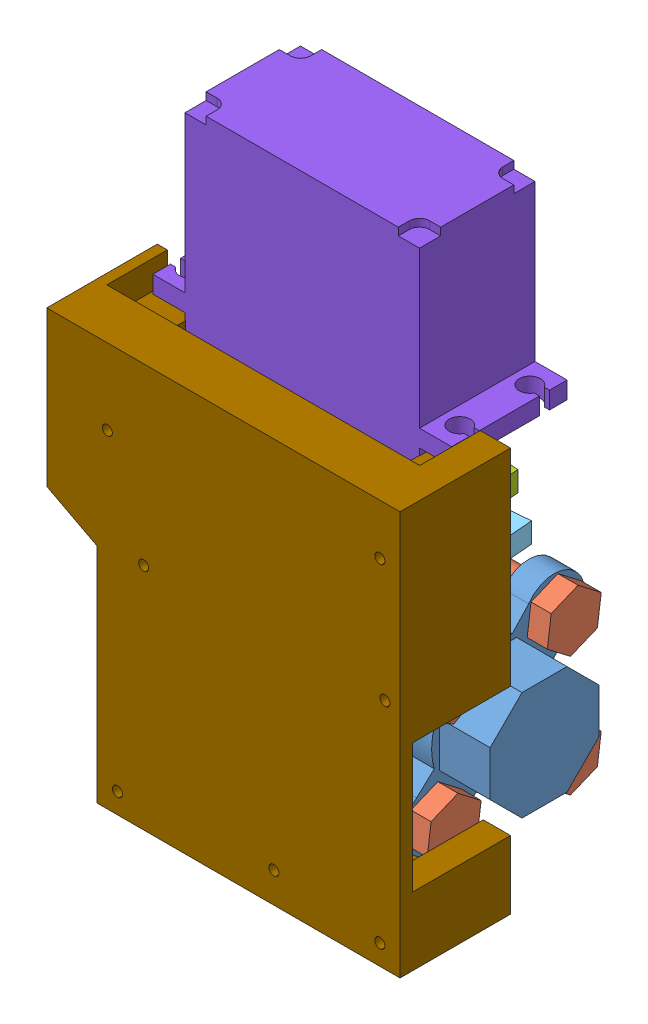
SolidWorks assembly Sharpe 39036 asm, configuration Default. Lengths in mm.
Overall size (89.2 141.62 60.37).
18 component instances, 9 part files, 35 mates.
Components (placement in the parent):
- Sharpe 39036-1: Sharpe 39036 [Default] at (-14.0964 -12.8458 82.9356) size (63.5 64.02 45.72)
- Sharpe 39036 Bolt-1: Sharpe 39036 Bolt [Default] at (29.0836 2.2672 98.0486) x (-1 0 0) z (0 -0.872825 -0.488034) size (53.34 14.66 12.7)
- Sharpe 39036 nut-1: Sharpe 39036 nut [Default] at (-22.6054 2.2672 98.0486) size (6.35 14.66 12.7)
- Sharpe 39036 washer-2: Sharpe 39036 washer [Default] at (-16.2554 2.2672 98.0486) size (2.16 13.21 13.21)
- Sharpe 39036 washer-3: Sharpe 39036 washer [Default] at (-16.2554 2.2672 67.8226) size (2.16 13.21 13.21)
- Sharpe 39036 nut-2: Sharpe 39036 nut [Default] at (-22.6054 -27.9588 98.0486) size (6.35 14.66 12.7)
- Sharpe 39036 Bolt-2: Sharpe 39036 Bolt [Default] at (29.0836 -27.9588 98.0486) x (-1 0 0) z (0 -0.924225 -0.381849) size (53.34 14.66 12.7)
- Sharpe 39036 Bolt-3: Sharpe 39036 Bolt [Default] at (29.0836 2.2672 67.8226) x (-1 0 0) z (0 -0.924225 -0.381849) size (53.34 14.66 12.7)
- Sharpe 39036 Bolt-4: Sharpe 39036 Bolt [Default] at (29.0836 -27.9588 67.8226) x (-1 0 0) z (0 -0.924225 -0.381849) size (53.34 14.66 12.7)
- Sharpe 39036 nut-3: Sharpe 39036 nut [Default] at (-22.6054 2.2672 67.8226) size (6.35 14.66 12.7)
- Sharpe 39036 nut-4: Sharpe 39036 nut [Default] at (-22.6054 -27.9588 67.8226) size (6.35 14.66 12.7)
- Sharpe 39036 washer-4: Sharpe 39036 washer [Default] at (-16.2554 -27.9588 67.8226) size (2.16 13.21 13.21)
- Sharpe 39036 washer-5: Sharpe 39036 washer [Default] at (-16.2554 -27.9588 98.0486) size (2.16 13.21 13.21)
- Horn adapter-1: Horn adapter [Default] at (4.9536 18.539 82.6516) x (-0.996749 0 0.08057) z (-0.08057 0 -0.996749) size (38.1 5.08 16.76)
- 90473A210_LOW-STRENGTH STEEL HEX NUT-1: 90473A210_LOW-STRENGTH STEEL HEX NUT [90473A210] at (4.7267 26.9925 82.6761) x (1 0 0) z (0 1 0) size (12.7 14.66 8.49)
- Servo Horn Mod-1: Servo Horn Mod [Default] at (4.9536 36.5381 82.6516) x (-0.996749 0 0.08057) z (0.08057 0 0.996749) size (37.59 7.67 15.49)
- PowerHD 1235MG-1: PowerHD 1235MG [Default] at (27.5723 54.1403 97.1931) x (-1 0 0) z (0 0 1) size (75.18 62.31 29.08)
- Housing-Front 1.0-1: Housing-Front 1.0 [Default] at (36.402 -46.332 115.818) size (88.9 101.6 27.81)
Mates (geometry in assembly coordinates):
- Coincident5: coincident anti-aligned: plane of Sharpe 39036-1 through (24.0036 -12.8458 82.9356) normal (1 0 0); plane of Sharpe 39036 Bolt-1 through (24.0036 2.2672 98.0486) normal (-1 0 0)
- Concentric4: concentric anti-aligned: cylinder of Sharpe 39036-1 through (24.0036 2.2672 98.0486) axis (-1 0 0) radius 4.7307; cylinder of Sharpe 39036 Bolt-1 through (-24.2564 2.2672 98.0486) axis (1 0 0) radius 3.9688
- Coincident6: coincident anti-aligned: plane of Sharpe 39036-1 through (-14.0964 -12.8458 82.9356) normal (-1 0 0); plane of Sharpe 39036 washer-2 through (-14.0964 2.2672 98.0486) normal (1 0 0)
- Coincident7: coincident aligned: cylinder of Sharpe 39036 Bolt-1 through (-24.2564 2.2672 98.0486) axis (1 0 0) radius 3.9688; circle of Sharpe 39036 washer-2
- Coincident8: coincident anti-aligned: plane of Sharpe 39036 nut-1 through (-16.2554 2.2672 98.0486) normal (1 0 0); plane of Sharpe 39036 washer-2 through (-16.2554 2.2672 98.0486) normal (-1 0 0)
- Concentric5: concentric anti-aligned: cylinder of Sharpe 39036 Bolt-1 through (-24.2564 2.2672 98.0486) axis (1 0 0) radius 3.9688; cylinder of Sharpe 39036 nut-1 through (-16.2554 2.2672 98.0486) axis (-1 0 0) radius 3.9688
- Coincident9: coincident anti-aligned: plane of Sharpe 39036-1 through (24.0036 -12.8458 82.9356) normal (1 0 0); plane of Sharpe 39036 Bolt-2 through (24.0036 -27.9588 98.0486) normal (-1 0 0)
- Concentric6: concentric anti-aligned: cylinder of Sharpe 39036-1 through (24.0036 -27.9588 98.0486) axis (-1 0 0) radius 4.7307; cylinder of Sharpe 39036 Bolt-2 through (-24.2564 -27.9588 98.0486) axis (1 0 0) radius 3.9688
- Coincident10: coincident anti-aligned: plane of Sharpe 39036-1 through (-14.0964 -12.8458 82.9356) normal (-1 0 0); plane of Sharpe 39036 washer-5 through (-14.0964 -27.9588 98.0486) normal (1 0 0)
- Concentric7: concentric anti-aligned: cylinder of Sharpe 39036 Bolt-2 through (-24.2564 -27.9588 98.0486) axis (1 0 0) radius 3.9688; cylinder of Sharpe 39036 washer-5 through (-14.0964 -27.9588 98.0486) axis (-1 0 0) radius 3.9688
- Coincident11: coincident anti-aligned: plane of Sharpe 39036 nut-2 through (-16.2554 -27.9588 98.0486) normal (1 0 0); circle of Sharpe 39036 washer-5
- Concentric8: concentric anti-aligned: cylinder of Sharpe 39036 nut-2 through (-16.2554 -27.9588 98.0486) axis (-1 0 0) radius 3.9688; cylinder of Sharpe 39036 Bolt-2 through (-24.2564 -27.9588 98.0486) axis (1 0 0) radius 3.9688
- Coincident12: coincident anti-aligned: plane of Sharpe 39036-1 through (24.0036 -12.8458 82.9356) normal (1 0 0); plane of Sharpe 39036 Bolt-3 through (24.0036 2.2672 67.8226) normal (-1 0 0)
- Concentric9: concentric anti-aligned: cylinder of Sharpe 39036-1 through (24.0036 2.2672 67.8226) axis (-1 0 0) radius 4.7307; cylinder of Sharpe 39036 Bolt-3 through (-24.2564 2.2672 67.8226) axis (1 0 0) radius 3.9688
- Coincident13: coincident anti-aligned: plane of Sharpe 39036-1 through (24.0036 -12.8458 82.9356) normal (1 0 0); plane of Sharpe 39036 Bolt-4 through (24.0036 -27.9588 67.8226) normal (-1 0 0)
- Concentric10: concentric anti-aligned: cylinder of Sharpe 39036-1 through (24.0036 -27.9588 67.8226) axis (-1 0 0) radius 4.7307; cylinder of Sharpe 39036 Bolt-4 through (-24.2564 -27.9588 67.8226) axis (1 0 0) radius 3.9688
- Coincident14: coincident anti-aligned: plane of Sharpe 39036-1 through (-14.0964 -12.8458 82.9356) normal (-1 0 0); plane of Sharpe 39036 washer-3 through (-14.0964 2.2672 67.8226) normal (1 0 0)
- Concentric11: concentric anti-aligned: cylinder of Sharpe 39036 washer-3 through (-14.0964 2.2672 67.8226) axis (-1 0 0) radius 3.9688; cylinder of Sharpe 39036 Bolt-3 through (-24.2564 2.2672 67.8226) axis (1 0 0) radius 3.9688
- Coincident15: coincident anti-aligned: plane of Sharpe 39036-1 through (-14.0964 -12.8458 82.9356) normal (-1 0 0); plane of Sharpe 39036 washer-4 through (-14.0964 -27.9588 67.8226) normal (1 0 0)
- Concentric12: concentric anti-aligned: cylinder of Sharpe 39036 Bolt-4 through (-24.2564 -27.9588 67.8226) axis (1 0 0) radius 3.9688; cylinder of Sharpe 39036 washer-4 through (-14.0964 -27.9588 67.8226) axis (-1 0 0) radius 3.9688
- Coincident16: coincident anti-aligned: plane of Sharpe 39036 washer-3 through (-16.2554 2.2672 67.8226) normal (-1 0 0); plane of Sharpe 39036 nut-3 through (-16.2554 2.2672 67.8226) normal (1 0 0)
- Concentric13: concentric anti-aligned: cylinder of Sharpe 39036 Bolt-3 through (-24.2564 2.2672 67.8226) axis (1 0 0) radius 3.9688; cylinder of Sharpe 39036 nut-3 through (-16.2554 2.2672 67.8226) axis (-1 0 0) radius 3.9688
- Coincident17: coincident anti-aligned: plane of Sharpe 39036 nut-4 through (-16.2554 -27.9588 67.8226) normal (1 0 0); plane of Sharpe 39036 washer-4 through (-16.2554 -27.9588 67.8226) normal (-1 0 0)
- Coincident18: coincident aligned: cylinder of Sharpe 39036 Bolt-4 through (-24.2564 -27.9588 67.8226) axis (1 0 0) radius 3.9688; circle of Sharpe 39036 nut-4
- Coincident19: coincident anti-aligned: plane of Sharpe 39036-1 through (4.9536 18.539 82.6516) normal (0 1 0); plane of Horn adapter-1 through (4.9536 18.539 82.6516) normal (0 -1 0)
- Coincident23: coincident anti-aligned: plane of Horn adapter-1 through (4.9536 23.619 82.6516) normal (0 1 0); plane of 90473A210_LOW-STRENGTH STEEL HEX NUT-1 through (-1.6233 23.619 79.01) normal (0 -1 0)
- Concentric17: concentric anti-aligned: cylinder of Horn adapter-1 through (19.9162 23.619 81.4422) axis (0 -1 0) radius 1.2446; cylinder of Servo Horn Mod-1 through (19.9162 31.4581 81.4422) axis (0 1 0) radius 1.2446
- Concentric20: concentric anti-aligned: cylinder of Servo Horn Mod-1 through (4.9536 38.0367 82.6516) axis (0 -1 0) radius 4.1656; cylinder of PowerHD 1235MG-1 through (4.9536 39.2051 82.6516) axis (0 1 0) radius 9.7155
- Concentric23: concentric anti-aligned: cylinder of Horn adapter-1 through (-10.009 23.619 83.8611) axis (0 -1 0) radius 1.2446; cylinder of Servo Horn Mod-1 through (-10.009 31.4581 83.8611) axis (0 1 0) radius 1.2446
- Concentric24: concentric anti-aligned: cylinder of Horn adapter-1 through (19.9162 23.619 81.4422) axis (0 -1 0) radius 1.2446; cylinder of Servo Horn Mod-1 through (19.9162 31.4581 81.4422) axis (0 1 0) radius 1.2446
- Coincident29: coincident anti-aligned: plane of 90473A210_LOW-STRENGTH STEEL HEX NUT-1 through (-1.6233 30.3659 79.01) normal (0 1 0); plane of Servo Horn Mod-1 through (4.9536 30.3659 82.6516) normal (0 -1 0)
- Parallel4: parallel anti-aligned: plane of 90473A210_LOW-STRENGTH STEEL HEX NUT-1 through (-1.6233 30.3659 79.01) normal (0 1 0); plane of Servo Horn Mod-1 through (34.8788 31.4581 80.2327) normal (0 -1 0)
- Parallel6: parallel aligned: plane of Sharpe 39036-1 through (36.7036 -12.8458 82.9356) normal (1 0 0); plane of PowerHD 1235MG-1 through (19.4951 93.3833 68.1101) normal (1 0 0)
- Concentric28: concentric anti-aligned: cylinder of Sharpe 39036-1 through (4.9536 18.539 82.6516) axis (0 -1 0) radius 4.6736; cylinder of Servo Horn Mod-1 through (4.9536 30.3659 82.6516) axis (0 1 0) radius 4.1656
- Coincident30: coincident anti-aligned: plane of Servo Horn Mod-1 through (4.9536 32.9821 82.6516) normal (0 1 0); plane of PowerHD 1235MG-1 through (27.5723 32.9821 97.1931) normal (0 -1 0)
